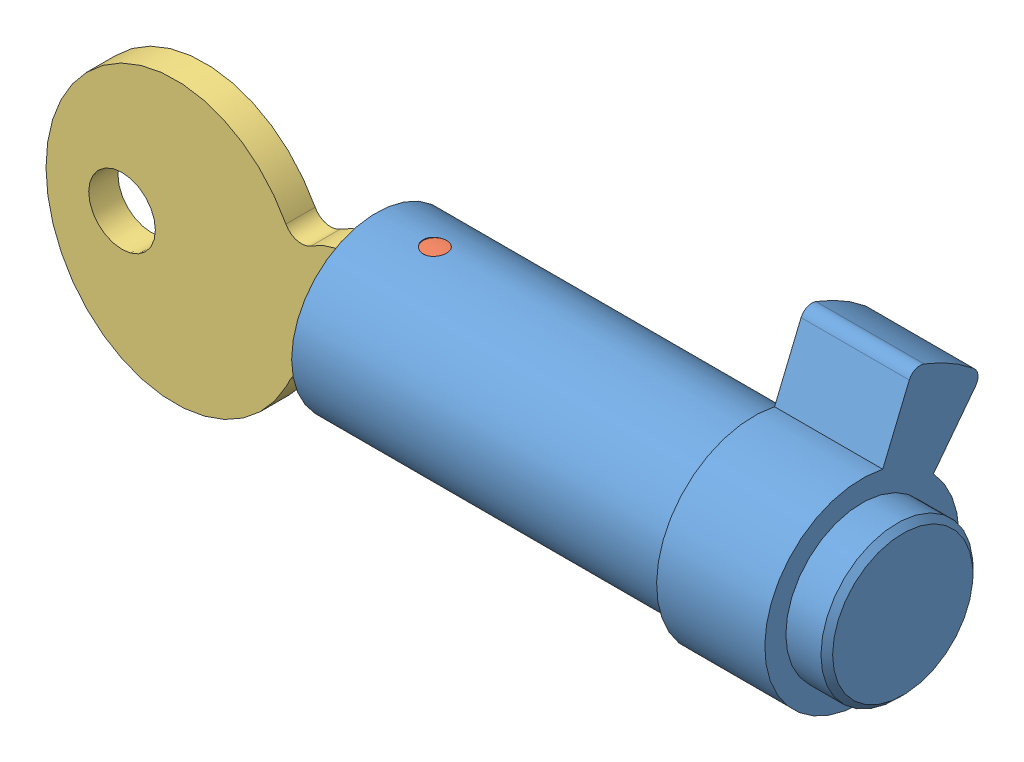
SolidWorks assembly core_sub-assembly_g, configuration Default. Lengths in mm.
Overall size (72 28.44 18.24).
3 component instances, 3 part files, 5 mates.
Components (placement in the parent):
- core_c-1: core_c [one-pair_of_pins] at origin size (45.24 22.49 18.24)
- lower_half_pin_x-depth_2-1: lower_half_pin_x-depth_2 [Default] at (5 7.25 0) x (0.558318 0 -0.829627) z (0.829627 0 0.558318) size (2 6.1 2)
- key_f-1: key_f [Default] at (0 -2.25 0) x (1 0 0) z (0 -1 0) size (59.59 2.5 24)
Mates (geometry in assembly coordinates):
- round: concentric anti-aligned: cylinder of core_c-1 through (5 35 0) axis (0 -1 0) radius 1; cylinder of lower_half_pin_x-depth_2-1 through (5 1.15 0) axis (0 1 0) radius 1
- bottom: coincident anti-aligned: plane of core_c-1 through (32.25 -6.25 -1.25) normal (0 1 0); plane of key_f-1 through (0 -6.25 1.25) normal (0 -1 0)
- side: coincident anti-aligned: plane of core_c-1 through (32.25 2 -1.25) normal (0 0 1); plane of key_f-1 through (-16 -2.25 -1.25) normal (0 0 -1)
- front: coincident anti-aligned: plane of core_c-1 through (0 0 0) normal (-1 0 0); plane of key_f-1 through (0 2 1.25) normal (1 0 0)
- cut: coincident anti-aligned: plane of lower_half_pin_x-depth_2-1 through (5 1.15 0) normal (0 -1 0); plane of key_f-1 through (4.5 1.15 1.25) normal (0 1 0)
